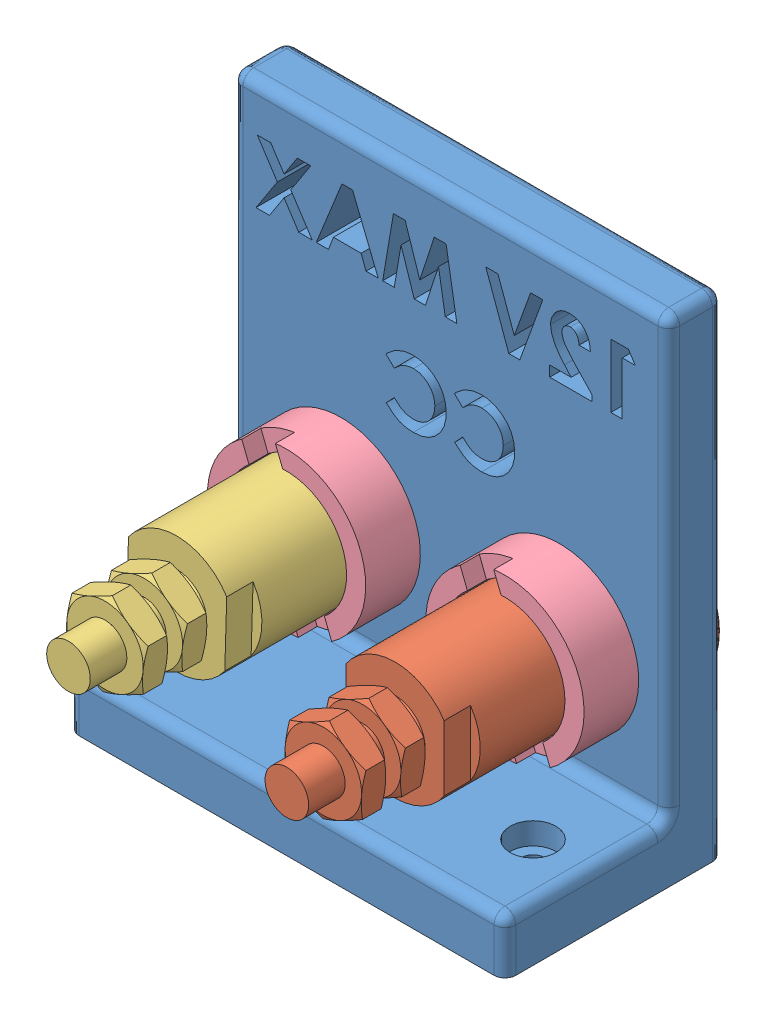
SolidWorks assembly alimentation, configuration Défaut. Lengths in mm.
Overall size (40 45 32.77).
5 component instances, 4 part files, 8 mates.
Components (placement in the parent):
- alimentation_support-1: alimentation_support [Défaut] at (-10.5748 2.0727 30) size (40 45 20)
- Fiche banane noir-1: Fiche banane noir [Default] at (-0.8911 1.5817 37.6675) x (1 0 0) z (0 1 0) size (14.4 32.77 14.4)
- Fiche banane rouge-1: Fiche banane rouge [Default] at (-20.9056 1.5913 37.6675) x (0.999557 -0.02976 0) z (0.02976 0.999557 0) size (14.4 32.77 14.4)
- Fiche banane ecrou-1: Fiche banane ecrou [Default] at (-20.4707 2.6475 39.6675) x (-0.923728 -0.383049 0) z (0.383049 -0.923728 0) size (14.5 5 14.5)
- Fiche banane ecrou-2: Fiche banane ecrou [Default] at (-0.4707 2.6475 39.6675) x (-0.923728 -0.383049 0) z (0.383049 -0.923728 0) size (14.5 5 14.5)
Mates (geometry in assembly coordinates):
- Coaxiale1: concentric anti-aligned: cylinder of support_alimentation-1 through (-20.5748 2.0727 35) axis (0 0 -1) radius 5.5; cylinder of Fiche banane rouge-1 through (-20.5748 2.0727 30) axis (0 0 1) radius 5.4
- Coaxiale2: concentric anti-aligned: cylinder of support_alimentation-1 through (-0.5748 2.0727 35) axis (0 0 -1) radius 5.5; cylinder of Fiche banane noir-1 through (-0.5748 2.0727 30) axis (0 0 1) radius 5.4
- Coïncidente1: coincident anti-aligned: plane of support_alimentation-1 through (-10.5748 2.0727 30) normal (0 0 -1); plane of Fiche banane noir-1 through (-0.5748 2.0727 30) normal (0 0 1)
- Coïncidente2: coincident anti-aligned: plane of support_alimentation-1 through (-10.5748 2.0727 30) normal (0 0 -1); plane of Fiche banane rouge-1 through (-20.5748 2.0727 30) normal (0 0 1)
- Coaxiale3: concentric aligned: cylinder of Fiche banane noir-1 through (-0.5748 2.0727 30) axis (0 0 1) radius 5.4; cylinder of Fiche banane ecrou-2 through (-0.5748 2.0727 35) axis (0 0 1) radius 5.5
- Coaxiale4: concentric aligned: cylinder of Fiche banane rouge-1 through (-20.5748 2.0727 30) axis (0 0 1) radius 5.4; cylinder of Fiche banane ecrou-1 through (-20.5748 2.0727 35) axis (0 0 1) radius 5.5
- Coïncidente3: coincident anti-aligned: plane of support_alimentation-1 through (-10.5748 2.0727 35) normal (0 0 1); plane of Fiche banane ecrou-2 through (-0.5748 2.0727 35) normal (0 0 -1)
- Coïncidente4: coincident anti-aligned: plane of support_alimentation-1 through (-10.5748 2.0727 35) normal (0 0 1); plane of Fiche banane ecrou-1 through (-20.5748 2.0727 35) normal (0 0 -1)
